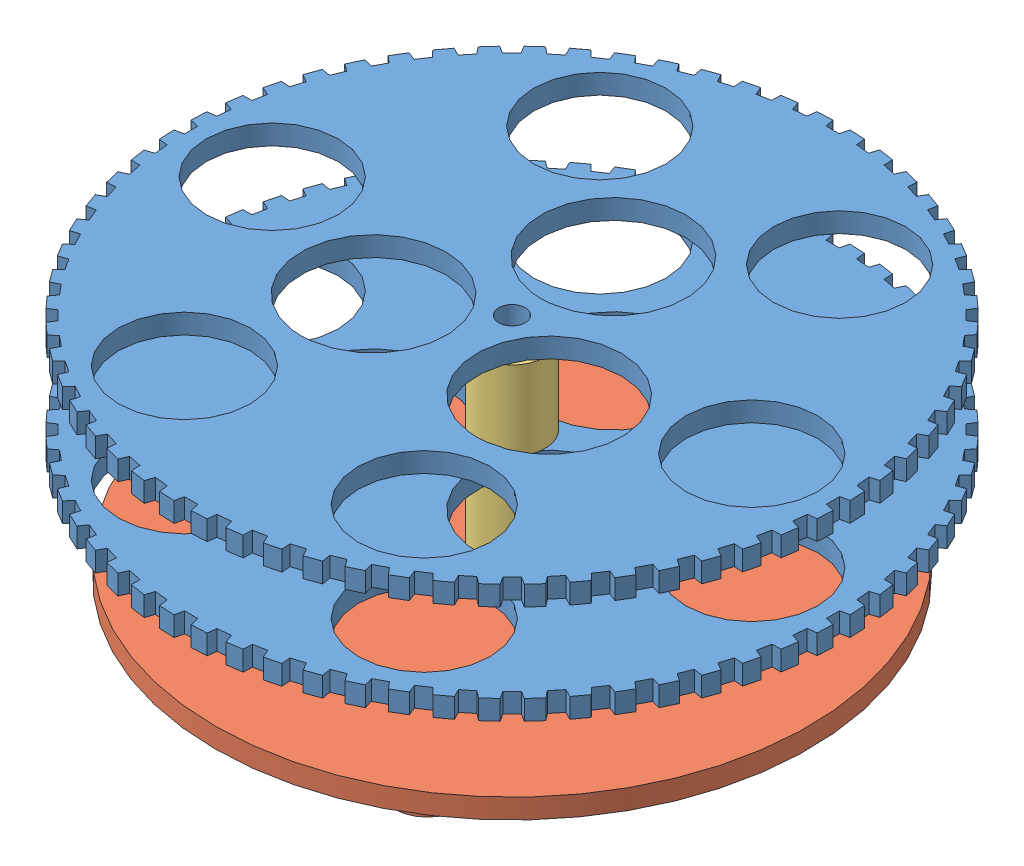
SolidWorks assembly Porte-tube, configuration Défaut. Lengths in mm.
Overall size (110.44 38.5 103.26).
5 component instances, 3 part files, 8 mates.
Components (placement in the parent):
- plateau-1: plateau [Défaut] at (-30.6105 4.7108 0) size (99.97 3 99.97)
- plateau-2: plateau [Défaut] at (-30.6105 19.7108 0) size (99.97 3 99.97)
- base support-1: base support [Défaut] at (-30.6105 -8.7892 0) size (90 7 90)
- traverse-1: traverse [Défaut] at (-30.6105 7.7108 0) size (10 12 10)
- traverse-5: traverse [Défaut] at (-30.6105 -7.2892 0) size (10 12 10)
Mates (geometry in assembly coordinates):
- Coaxiale1: concentric aligned: cylinder of plateau-1; cylinder of plateau-2
- Coaxiale2: concentric anti-aligned: cylinder of plateau-1; cylinder of base support-1
- Distance2: distance = 38.5 mm anti-aligned: plane of plateau-2 through (-30.6105 22.7108 0) normal (0 1 0); plane of base support-1 through (-30.6105 -15.7892 0) normal (0 -1 0)
- Coïncidente3: coincident anti-aligned: plane of plateau-2 through (-30.6105 19.7108 0) normal (0 -1 0); plane of traverse-1 through (-30.6105 19.7108 0) normal (0 1 0)
- Coaxiale3: concentric anti-aligned: cylinder of plateau-2; cylinder of traverse-1
- Coïncidente5: coincident anti-aligned: plane of ?; plane of ?
- Coïncidente6: coincident anti-aligned: plane of ?; plane of ?
- Coaxiale4: concentric anti-aligned: 
